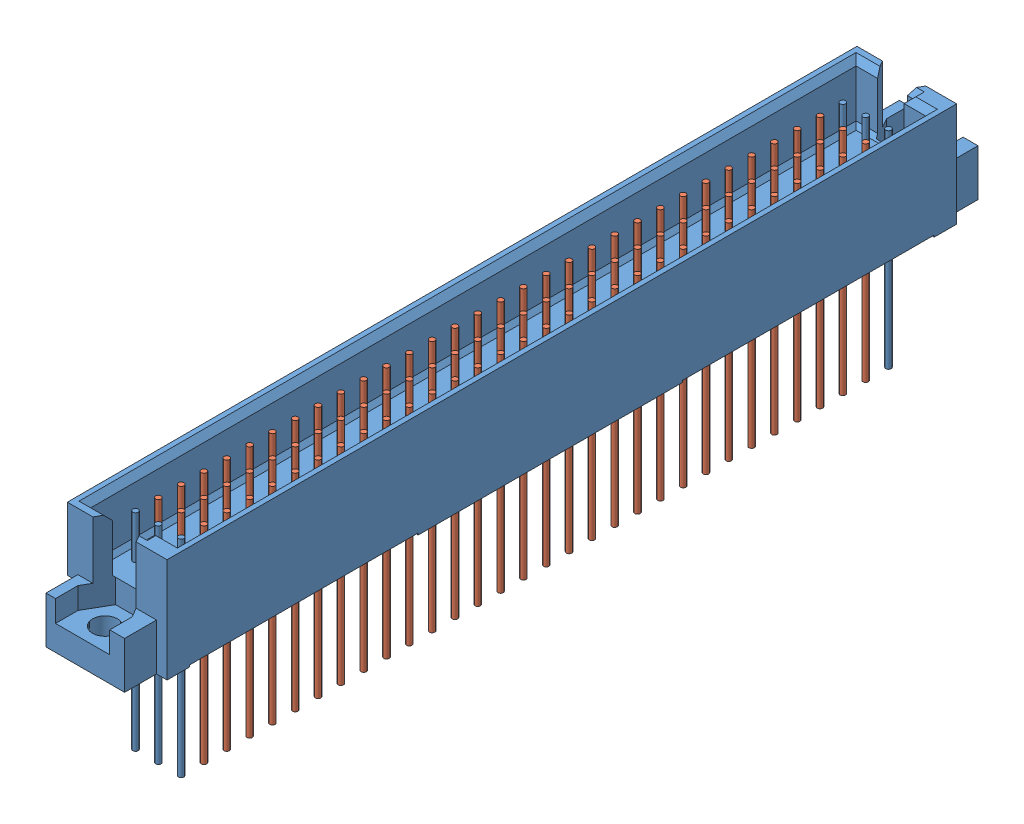
SolidWorks assembly 09731966907, configuration Default. Lengths in mm.
Overall size (11.1 24.6 95).
91 component instances, 2 part files, 5 mates.
Components (placement in the parent):
- 09731966907-1: 09731966907 [Default] at (5.85 10 -47.5) size (11.1 24.6 95)
- Pin-1: Pin [Default] at (2.84 -3 -36.83) size (0.6 23 0.6)
- Pin-2: Pin [Default] at (0.3 -3 -36.83) size (0.6 23 0.6)
- Pin-3: Pin [Default] at (-2.24 -3 -36.83) size (0.6 23 0.6)
- Pin-4: Pin [Default] at (2.84 -3 -34.29) size (0.6 23 0.6)
- Pin-5: Pin [Default] at (0.3 -3 -34.29) size (0.6 23 0.6)
- Pin-6: Pin [Default] at (-2.24 -3 -34.29) size (0.6 23 0.6)
- Pin-7: Pin [Default] at (2.84 -3 -31.75) size (0.6 23 0.6)
- Pin-8: Pin [Default] at (0.3 -3 -31.75) size (0.6 23 0.6)
- Pin-9: Pin [Default] at (-2.24 -3 -31.75) size (0.6 23 0.6)
- Pin-10: Pin [Default] at (2.84 -3 -29.21) size (0.6 23 0.6)
- Pin-11: Pin [Default] at (0.3 -3 -29.21) size (0.6 23 0.6)
- Pin-12: Pin [Default] at (-2.24 -3 -29.21) size (0.6 23 0.6)
- Pin-13: Pin [Default] at (2.84 -3 -26.67) size (0.6 23 0.6)
- Pin-14: Pin [Default] at (0.3 -3 -26.67) size (0.6 23 0.6)
- Pin-15: Pin [Default] at (-2.24 -3 -26.67) size (0.6 23 0.6)
- Pin-16: Pin [Default] at (2.84 -3 -24.13) size (0.6 23 0.6)
- Pin-17: Pin [Default] at (0.3 -3 -24.13) size (0.6 23 0.6)
- Pin-18: Pin [Default] at (-2.24 -3 -24.13) size (0.6 23 0.6)
- Pin-19: Pin [Default] at (2.84 -3 -21.59) size (0.6 23 0.6)
- Pin-20: Pin [Default] at (0.3 -3 -21.59) size (0.6 23 0.6)
- Pin-21: Pin [Default] at (-2.24 -3 -21.59) size (0.6 23 0.6)
- Pin-22: Pin [Default] at (2.84 -3 -19.05) size (0.6 23 0.6)
- Pin-23: Pin [Default] at (0.3 -3 -19.05) size (0.6 23 0.6)
- Pin-24: Pin [Default] at (-2.24 -3 -19.05) size (0.6 23 0.6)
- Pin-25: Pin [Default] at (2.84 -3 -16.51) size (0.6 23 0.6)
- Pin-26: Pin [Default] at (0.3 -3 -16.51) size (0.6 23 0.6)
- Pin-27: Pin [Default] at (-2.24 -3 -16.51) size (0.6 23 0.6)
- Pin-28: Pin [Default] at (2.84 -3 -13.97) size (0.6 23 0.6)
- Pin-29: Pin [Default] at (0.3 -3 -13.97) size (0.6 23 0.6)
- Pin-30: Pin [Default] at (-2.24 -3 -13.97) size (0.6 23 0.6)
- Pin-31: Pin [Default] at (2.84 -3 -11.43) size (0.6 23 0.6)
- Pin-32: Pin [Default] at (0.3 -3 -11.43) size (0.6 23 0.6)
- Pin-33: Pin [Default] at (-2.24 -3 -11.43) size (0.6 23 0.6)
- Pin-34: Pin [Default] at (2.84 -3 -8.89) size (0.6 23 0.6)
- Pin-35: Pin [Default] at (0.3 -3 -8.89) size (0.6 23 0.6)
- Pin-36: Pin [Default] at (-2.24 -3 -8.89) size (0.6 23 0.6)
- Pin-37: Pin [Default] at (2.84 -3 -6.35) size (0.6 23 0.6)
- Pin-38: Pin [Default] at (0.3 -3 -6.35) size (0.6 23 0.6)
- Pin-39: Pin [Default] at (-2.24 -3 -6.35) size (0.6 23 0.6)
- Pin-40: Pin [Default] at (2.84 -3 -3.81) size (0.6 23 0.6)
- Pin-41: Pin [Default] at (0.3 -3 -3.81) size (0.6 23 0.6)
- Pin-42: Pin [Default] at (-2.24 -3 -3.81) size (0.6 23 0.6)
- Pin-43: Pin [Default] at (2.84 -3 -1.27) size (0.6 23 0.6)
- Pin-44: Pin [Default] at (0.3 -3 -1.27) size (0.6 23 0.6)
- Pin-45: Pin [Default] at (-2.24 -3 -1.27) size (0.6 23 0.6)
- Pin-46: Pin [Default] at (2.84 -3 1.27) size (0.6 23 0.6)
- Pin-47: Pin [Default] at (0.3 -3 1.27) size (0.6 23 0.6)
- Pin-48: Pin [Default] at (-2.24 -3 1.27) size (0.6 23 0.6)
- Pin-49: Pin [Default] at (2.84 -3 3.81) size (0.6 23 0.6)
- Pin-50: Pin [Default] at (0.3 -3 3.81) size (0.6 23 0.6)
- Pin-51: Pin [Default] at (-2.24 -3 3.81) size (0.6 23 0.6)
- Pin-52: Pin [Default] at (2.84 -3 6.35) size (0.6 23 0.6)
- Pin-53: Pin [Default] at (0.3 -3 6.35) size (0.6 23 0.6)
- Pin-54: Pin [Default] at (-2.24 -3 6.35) size (0.6 23 0.6)
- Pin-55: Pin [Default] at (2.84 -3 8.89) size (0.6 23 0.6)
- Pin-56: Pin [Default] at (0.3 -3 8.89) size (0.6 23 0.6)
- Pin-57: Pin [Default] at (-2.24 -3 8.89) size (0.6 23 0.6)
- Pin-58: Pin [Default] at (2.84 -3 11.43) size (0.6 23 0.6)
- Pin-59: Pin [Default] at (0.3 -3 11.43) size (0.6 23 0.6)
- Pin-60: Pin [Default] at (-2.24 -3 11.43) size (0.6 23 0.6)
- Pin-61: Pin [Default] at (2.84 -3 13.97) size (0.6 23 0.6)
- Pin-62: Pin [Default] at (0.3 -3 13.97) size (0.6 23 0.6)
- Pin-63: Pin [Default] at (-2.24 -3 13.97) size (0.6 23 0.6)
- Pin-64: Pin [Default] at (2.84 -3 16.51) size (0.6 23 0.6)
- Pin-65: Pin [Default] at (0.3 -3 16.51) size (0.6 23 0.6)
- Pin-66: Pin [Default] at (-2.24 -3 16.51) size (0.6 23 0.6)
- Pin-67: Pin [Default] at (2.84 -3 19.05) size (0.6 23 0.6)
- Pin-68: Pin [Default] at (0.3 -3 19.05) size (0.6 23 0.6)
- Pin-69: Pin [Default] at (-2.24 -3 19.05) size (0.6 23 0.6)
- Pin-70: Pin [Default] at (2.84 -3 21.59) size (0.6 23 0.6)
- Pin-71: Pin [Default] at (0.3 -3 21.59) size (0.6 23 0.6)
- Pin-72: Pin [Default] at (-2.24 -3 21.59) size (0.6 23 0.6)
- Pin-73: Pin [Default] at (2.84 -3 24.13) size (0.6 23 0.6)
- Pin-74: Pin [Default] at (0.3 -3 24.13) size (0.6 23 0.6)
- Pin-75: Pin [Default] at (-2.24 -3 24.13) size (0.6 23 0.6)
- Pin-76: Pin [Default] at (2.84 -3 26.67) size (0.6 23 0.6)
- Pin-77: Pin [Default] at (0.3 -3 26.67) size (0.6 23 0.6)
- Pin-78: Pin [Default] at (-2.24 -3 26.67) size (0.6 23 0.6)
- Pin-79: Pin [Default] at (2.84 -3 29.21) size (0.6 23 0.6)
- Pin-80: Pin [Default] at (0.3 -3 29.21) size (0.6 23 0.6)
- Pin-81: Pin [Default] at (-2.24 -3 29.21) size (0.6 23 0.6)
- Pin-82: Pin [Default] at (2.84 -3 31.75) size (0.6 23 0.6)
- Pin-83: Pin [Default] at (0.3 -3 31.75) size (0.6 23 0.6)
- Pin-84: Pin [Default] at (-2.24 -3 31.75) size (0.6 23 0.6)
- Pin-85: Pin [Default] at (2.84 -3 34.29) size (0.6 23 0.6)
- Pin-86: Pin [Default] at (0.3 -3 34.29) size (0.6 23 0.6)
- Pin-87: Pin [Default] at (-2.24 -3 34.29) size (0.6 23 0.6)
- Pin-88: Pin [Default] at (2.84 -3 36.83) size (0.6 23 0.6)
- Pin-89: Pin [Default] at (0.3 -3 36.83) size (0.6 23 0.6)
- Pin-90: Pin [Default] at (-2.24 -3 36.83) size (0.6 23 0.6)
Mates (geometry in assembly coordinates):
- Coincident1: coincident aligned: plane of 09731966907-1 through (0 10 -47.5) normal (1 0 0)
- Coincident2: coincident anti-aligned: plane of 09731966907-1 through (5.85 10 0) normal (0 0 -1)
- Distance1: distance = 10 mm aligned: plane of 09731966907-1 through (5.85 10 -47.5) normal (0 1 0)
- Coincident4: coincident aligned: plane of 09731966907-1 through (-2.5438 20 39.6752) normal (0 1 0); plane of Pin-1 through (2.84 20 -36.83) normal (0 1 0)
- Concentric1: concentric anti-aligned: line of 09731966907-1 through (2.84 14.96 -36.83) axis (0 1 0); cylinder of Pin-1 through (2.84 20 -36.83) axis (0 -1 0) radius 0.3
